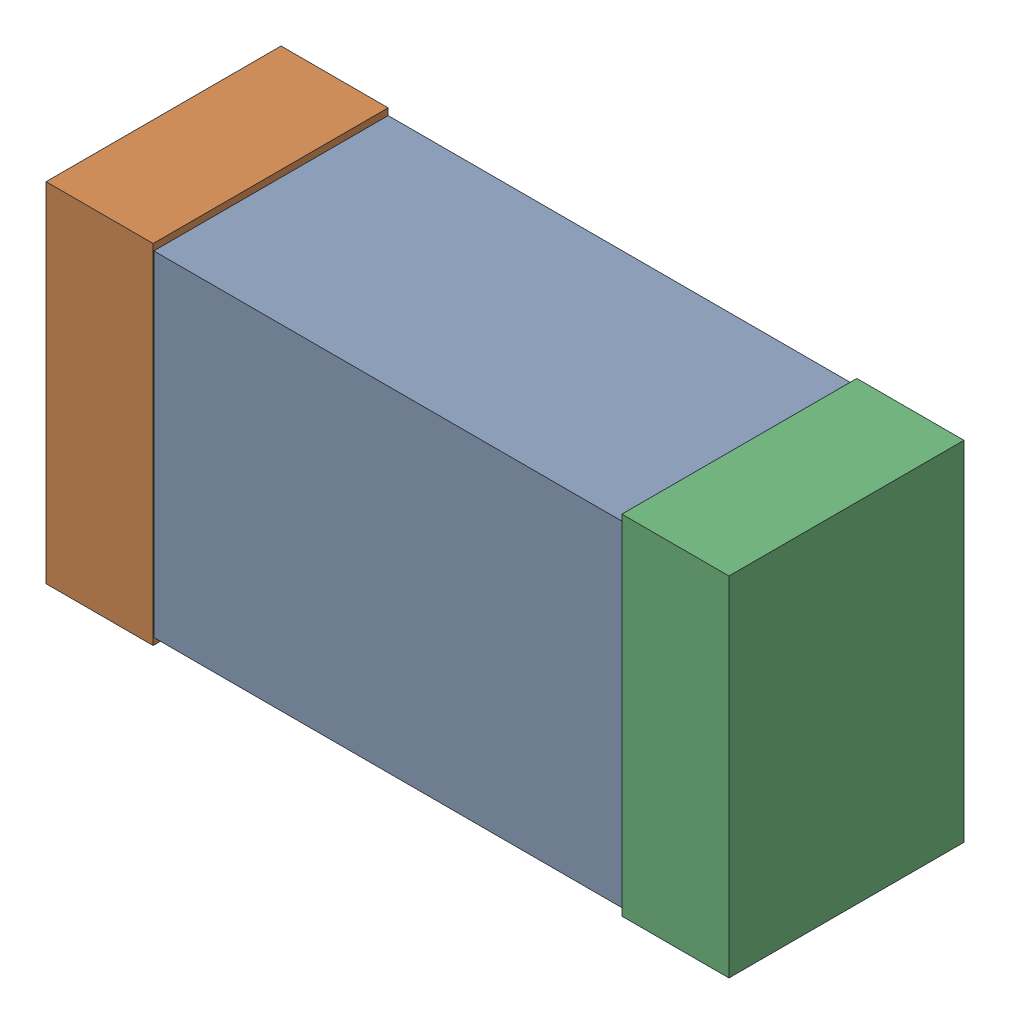
SolidWorks assembly D11, configuration Default. Lengths in mm.
Overall size (1.02 0.52 0.35).
6 component instances, 2 part files, 0 mates.
Components (placement in the parent):
- 870944640-1: 870944640 [Default] at (15.6202 1.0646 0) size (1 0.5 0.35)
  - Extruded_30-1: Extruded_30 [Default] at origin size (1 0.5 0.35)
- 870940480-1: 870940480 [Default] at (15.1902 1.0646 0) size (0.16 0.52 0.35)
  - Extruded-1: Extruded [Default] at origin size (0.16 0.52 0.35)
- 870940480-2: 870940480 [Default] at (16.0502 1.0646 0) size (0.16 0.52 0.35)
  - Extruded-1: Extruded [Default] at origin size (0.16 0.52 0.35)
